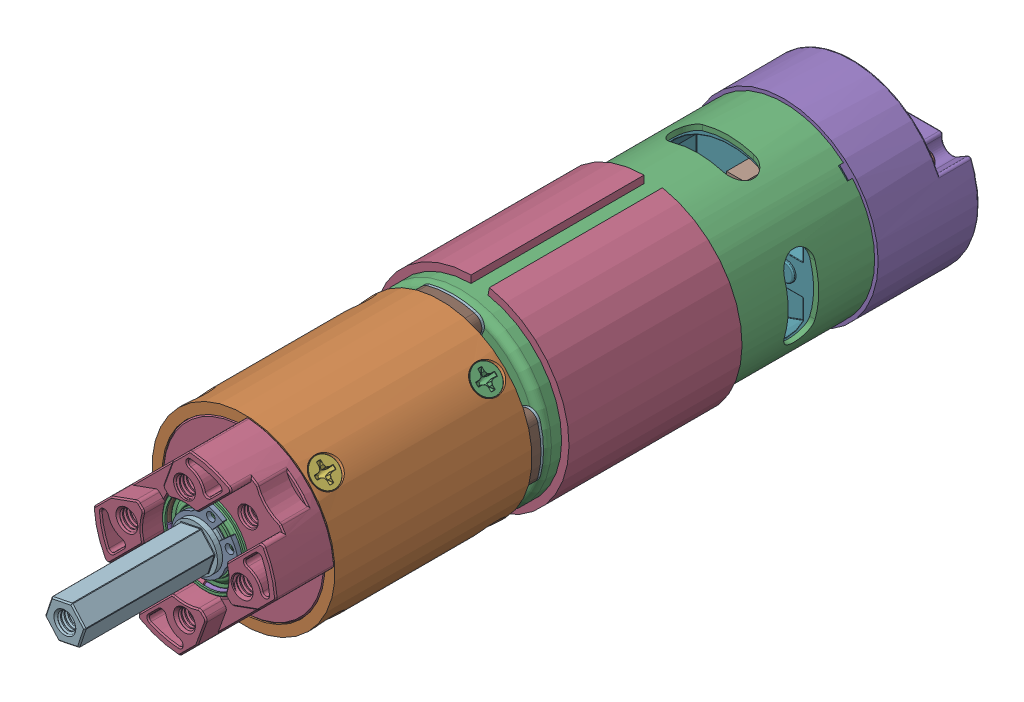
SolidWorks assembly 5303-2402-0071, configuration Default. Lengths in mm.
Overall size (50.88 50.88 161.25).
44 component instances, 22 part files, 0 mates.
Components (placement in the parent):
- Body-1: Body [Default] at origin size (38.5 38.5 81)
  - Bearing-1: Bearing [Default] at origin size (11 11 4)
    - OD-1: OD [Default] at origin size (11 11 4)
    - IR-1: IR [Default] at origin size (6 6 4)
  - Casing-1: Casing [Default] at origin size (35.6 35.6 69.5)
  - Ring-1: Ring [Default] at origin size (38.5 38.5 34)
  - Core-1: Core [Default] at origin size (22 21.62 81)
  - Fan-1: Fan [Default] at origin size (27.53 27.59 6.5)
  - Magnets-1: Magnets [Default] at origin size (33.6 30.57 41.5)
- Cap-1: Cap [Default] at origin size (37 37 30.95)
  - JST-XH-4POS-VERT-1: JST-XH-4POS-VERT [Default] at (2.8 12.25 -75.95) x (1 0 0) z (0 0 -1) size (12.4 5.75 10.4)
    - Plastic-1: Plastic [Default] at (0 -2.875 0) size (12.4 5.75 7)
    - Pin-1: Pin [Default] at (3.75 -0.525 1.6) size (0.64 0.64 10)
    - Pin-2: Pin [Default] at (-3.75 -0.525 1.6) size (0.64 0.64 10)
    - Pin-3: Pin [Default] at (-1.25 -0.525 1.6) size (0.64 0.64 10)
    - Pin-4: Pin [Default] at (1.25 -0.525 1.6) size (0.64 0.64 10)
  - Encoder Cap-1: Encoder Cap [Default] at origin size (37 37 19.95)
  - Stopper-1: Stopper [Default] at origin size (34.25 33.6 11)
  - Screw-1: Screw [Default] at (41.264 8.1646 3.9905) x (-0.882398 0 0.470504) z (0 1 0) size (5.37 7.47 3.5)
  - Screw-2: Screw [Default] at (-41.264 -8.1646 3.9905) x (0.882398 0 0.470504) z (0 -1 0) size (5.37 7.47 3.5)
- Spacers-1: Spacers [Default] at origin size (35.5 35.5 2.5)
  - PCB-1: PCB [Default] at (-11.099 -71.9658 -4) size (35.5 35.5 2)
  - Steel-1: Steel [Default] at (-11.099 -71.9658 -4.5) size (35.5 35.5 0.5)
- Gearbox-1: Gearbox [Default] at (90.9779 96.8868 -24.0285) x (0.707107 0.707107 0) z (0.707107 -0.707107 0) size (36 76.68 35.96)
  - Simple-1: Simple [Default] at (-74.1198 0.9931 -10.6145) size (36 73.8 35.96)
    - 5303 Gearbox Base-1: 5303 Gearbox Base [Default] at (-58.7206 21.0354 14.7927) size (31.9 5.6 31.9)
    - 5303 Gearbox Barrel (4 stage, simple)_Gear Blank-1: 5303 Gearbox Barrel (4 stage, simple)_Gear Blank [Default] at (-58.7206 99.2654 14.7927) x (1 0 0) z (0 -1 0) size (35.96 35.96 38.7)
    - 5303 Gearbox Barrel Screw (M3 x 8mm length Flat Head)_92010A118-1: 5303 Gearbox Barrel Screw (M3 x 8mm length Flat Head)_92010A118 [Default] at (-58.7206 24.5354 30.8757) x (0.002439 -0.999997 0) z (0 0 1) size (5.46 5.46 8.05)
    - 5303 Gearbox Face-1: 5303 Gearbox Face [Default] at (-58.7206 54.2354 14.7927) size (36 17.1 31.9)
    - 5303 Gearbox Bearing-1: 5303 Gearbox Bearing [Default] at (-58.7206 62.3354 14.7927) size (17 5 17)
    - 5303 Gearbox Shaft (23.5mm Length, Simple)-1: 5303 Gearbox Shaft (23.5mm Length, Simple) [Default] at (-58.7206 50.8754 14.7927) x (0.894773 0 -0.44652) z (0.44652 0 0.894773) size (8.97 40.6 8.97)
    - 5303 Gearbox Snap Ring-1: 5303 Gearbox Snap Ring [Default] at (-58.7206 67.4104 14.7927) x (0 1 0) z (0 0 1) size (0.85 13.06 10.66)
    - 5303 Gearbox Barrel Screw (M3 x 8mm length Flat Head)_92010A118-2: 5303 Gearbox Barrel Screw (M3 x 8mm length Flat Head)_92010A118 [Default] at (-58.7206 56.2354 30.8757) x (-0.002439 -0.999997 0) z (0 0 1) size (5.46 5.46 8.05)
    - 5303 Gearbox Barrel Screw (M3 x 8mm length Flat Head)_92010A118-3: 5303 Gearbox Barrel Screw (M3 x 8mm length Flat Head)_92010A118 [Default] at (-42.6376 24.5354 14.7927) x (0 -0.999997 -0.002439) z (1 0 0) size (5.46 5.46 8.05)
    - 5303 Gearbox Barrel Screw (M3 x 8mm length Flat Head)_92010A118-4: 5303 Gearbox Barrel Screw (M3 x 8mm length Flat Head)_92010A118 [Default] at (-58.7206 24.5354 -1.2903) x (-0.002439 -0.999997 0) z (0 0 -1) size (5.46 5.46 8.05)
    - 5303 Gearbox Barrel Screw (M3 x 8mm length Flat Head)_92010A118-5: 5303 Gearbox Barrel Screw (M3 x 8mm length Flat Head)_92010A118 [Default] at (-74.8037 24.5354 14.7927) x (0 -0.999997 0.002439) z (-1 0 0) size (5.46 5.46 8.05)
    - 5303 Gearbox Barrel Screw (M3 x 8mm length Flat Head)_92010A118-6: 5303 Gearbox Barrel Screw (M3 x 8mm length Flat Head)_92010A118 [Default] at (-42.6376 56.2354 14.7927) x (0 -0.999997 0.002439) z (1 0 0) size (5.46 5.46 8.05)
    - 5303 Gearbox Barrel Screw (M3 x 8mm length Flat Head)_92010A118-7: 5303 Gearbox Barrel Screw (M3 x 8mm length Flat Head)_92010A118 [Default] at (-58.7206 56.2354 -1.2903) x (0.002439 -0.999997 0) z (0 0 -1) size (5.46 5.46 8.05)
    - 5303 Gearbox Barrel Screw (M3 x 8mm length Flat Head)_92010A118-8: 5303 Gearbox Barrel Screw (M3 x 8mm length Flat Head)_92010A118 [Default] at (-74.8037 56.2354 14.7927) x (0 -0.999997 -0.002439) z (-1 0 0) size (5.46 5.46 8.05)
    - 5303 Gearbox Bearing-2: 5303 Gearbox Bearing [Default] at (-58.7206 54.2354 14.7927) size (17 5 17)
  - Gearbox Base Mounting Screw M3 x 5mm length SHCS)_91290A110-1: Gearbox Base Mounting Screw M3 x 5mm length SHCS)_91290A110 [Default] at (-141.6792 19.1485 13.0171) x (0.056382 0 0.998409) z (0 -1 0) size (5.5 5.5 8)
  - Gearbox Base Mounting Screw M3 x 5mm length SHCS)_91290A110-2: Gearbox Base Mounting Screw M3 x 5mm length SHCS)_91290A110 [Default] at (-124.0016 19.1485 13.0171) x (0.998409 0 -0.056382) z (0 -1 0) size (5.5 5.5 8)
  - Gearbox Base Mounting Screw M3 x 5mm length SHCS)_91290A110-3: Gearbox Base Mounting Screw M3 x 5mm length SHCS)_91290A110 [Default] at (-124.0016 19.1485 -4.6606) x (-0.056382 0 -0.998409) z (0 -1 0) size (5.5 5.5 8)
  - Gearbox Base Mounting Screw M3 x 5mm length SHCS)_91290A110-4: Gearbox Base Mounting Screw M3 x 5mm length SHCS)_91290A110 [Default] at (-141.6792 19.1485 -4.6606) x (-0.998409 0 0.056382) z (0 -1 0) size (5.5 5.5 8)
